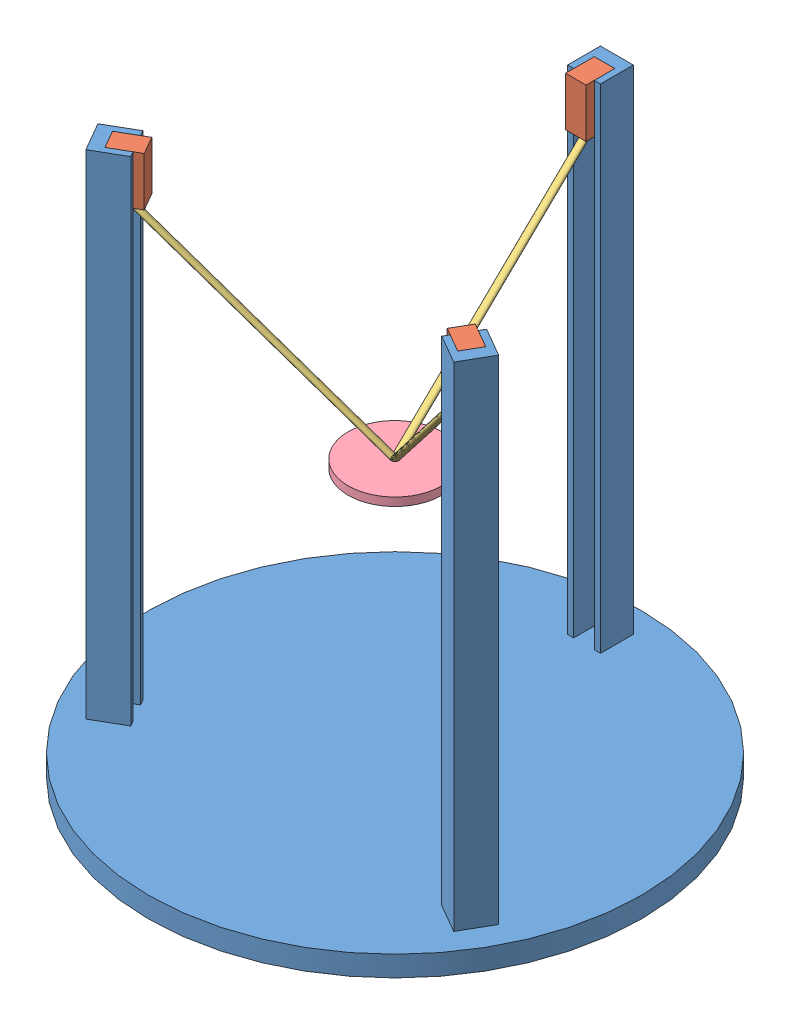
SolidWorks assembly Assem1, configuration Default. Lengths in mm.
Overall size (600 625 600).
8 component instances, 4 part files, 15 mates.
Components (placement in the parent):
- delta-1: delta [Default] at (107.0496 118.68 184.1639) size (600 625 600)
- Part3-1: Part3 [Default] at (-113.7869 118.68 311.6639) x (-0.5 0 -0.866025) z (0.866025 0 -0.5) size (25 59.5 35)
- Part3-2: Part3 [Default] at (297.618 118.68 294.0897) x (0.5 0 -0.866025) z (0.866025 0 0.5) size (25 59.5 35)
- Part3-3: Part3 [Default] at (107.0496 118.68 -70.8361) size (25 59.5 35)
- Part4-1: Part4 [Default] at (-113.7869 684.1824 311.6639) x (0.5 0 0.866025) z (0 -1 0) size (214.38 127.45 230.5)
- Part5-1: Part5 [Default] at (107.0496 443.68 184.1639) x (1 0 0) z (0 1 0) size (113.99 113.99 10)
- Part4-2: Part4 [Default] at (327.886 684.1824 311.6639) x (0.5 0 -0.866025) z (0 -1 0) size (214.38 127.45 230.5)
- Part4-3: Part4 [Default] at (107.0496 684.1824 -70.8361) x (-1 0 0) z (0 -1 0) size (214.38 127.45 230.5)
Mates (geometry in assembly coordinates):
- Coincident7: coincident anti-aligned: plane of delta-1 through (-107.5155 143.68 322.5264) normal (0.866025 0 -0.5); plane of Part3-1 through (-113.7869 118.68 311.6639) normal (-0.866025 0 0.5)
- Coincident8: coincident anti-aligned: plane of delta-1 through (-120.0155 143.68 300.8757) normal (0.5 0 0.866025); plane of Part3-1 through (-89.7046 743.68 283.3757) normal (-0.5 0 -0.866025)
- Coincident10: coincident anti-aligned: plane of delta-1 through (94.5067 143.68 -45.8361) normal (1 0 0); plane of Part3-3 through (94.5067 743.68 -35.8361) normal (-1 0 0)
- Coincident11: coincident anti-aligned: plane of delta-1 through (94.5067 143.68 -70.8361) normal (0 0 1); plane of Part3-3 through (107.0496 118.68 -70.8361) normal (0 0 -1)
- Coincident12: coincident aligned: plane of delta-1 through (107.0496 743.68 184.1639) normal (0 1 0); plane of Part3-1 through (-77.2046 743.68 305.0264) normal (0 1 0)
- Coincident13: coincident aligned: plane of delta-1 through (107.0496 743.68 184.1639) normal (0 1 0); plane of Part3-3 through (94.5067 743.68 -35.8361) normal (0 1 0)
- Coincident14: coincident anti-aligned: plane of delta-1 through (312.5069 143.68 288.3015) normal (-0.5 0 0.866025); plane of Part3-2 through (334.1575 743.68 300.8015) normal (0.5 0 -0.866025)
- Coincident15: coincident anti-aligned: plane of delta-1 through (334.1575 143.68 300.8015) normal (-0.866025 0 -0.5); plane of Part3-2 through (327.9289 118.68 311.5897) normal (0.866025 0 0.5)
- Coincident16: coincident aligned: plane of delta-1 through (107.0496 743.68 184.1639) normal (0 1 0); plane of Part3-2 through (321.6575 743.68 322.4521) normal (0 1 0)
- InPlace3: in place: plane of Part3-1 through (-77.2046 684.1824 305.0264) normal (0 -1 0); plane of ? through (0 684.1824 0) normal (0 -1 0); moOrthogonalPlaneRef_w of Part3-1 through (-77.2046 684.1824 305.0264) normal (0 -1 0); unknown of ?; plane of Part3-1 through (-77.2046 684.1824 305.0264) normal (0 -1 0); line of ? through (-55 0 684.1824) axis (0 -1 0); plane of Part3-1 through (-77.2046 684.1824 305.0264) normal (0 -1 0); unknown of Part4-1
- Coincident17: coincident aligned: plane of Part3-1; plane of Part4-1
- Coincident18: coincident aligned: moOrthogonalPlaneRef_w of Part3-1 through (-113.7869 684.1824 311.6639) normal (-0.866025 0 0.5); plane of Part4-1
- Coincident19: coincident anti-aligned: moOrthogonalPlaneRef_w of Part3-1 through (-113.7869 684.1824 311.6639) normal (-0.5 0 -0.866025); plane of Part4-1
- Distance1: distance = 300 mm: plane of Part5-1 through (107.0496 443.68 184.1639) normal (0 -1 0); plane of delta-1 through (107.0496 143.68 184.1639) normal (0 1 0)
- Concentric1: concentric aligned: circle of delta-1; circle of Part5-1
